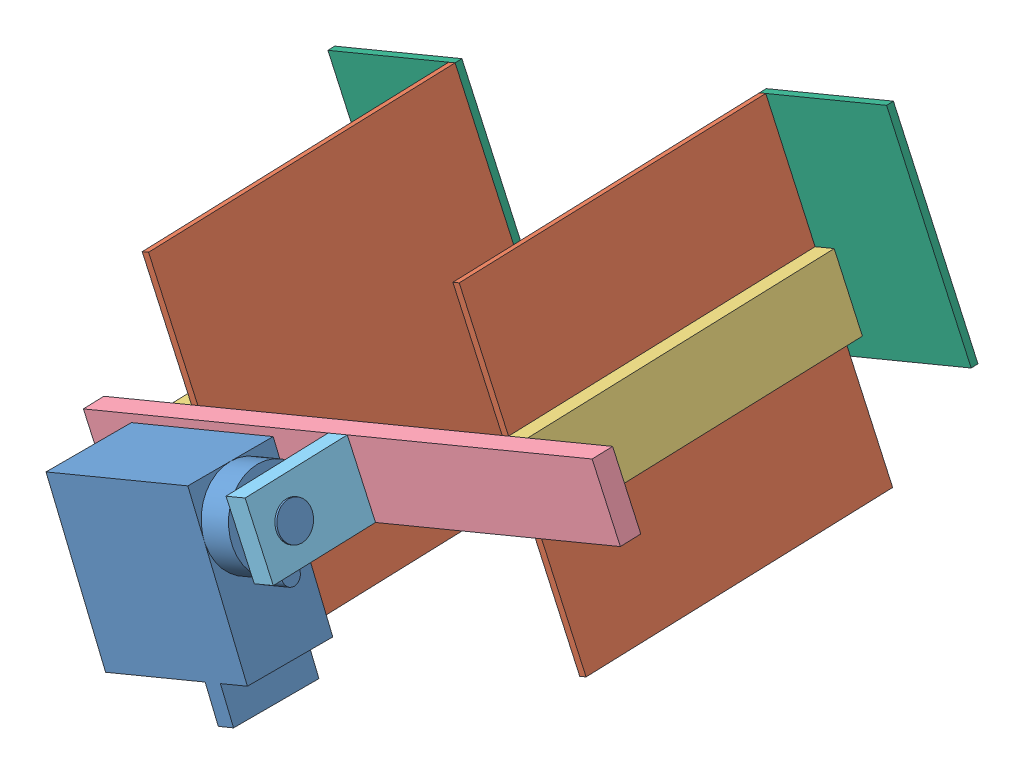
SolidWorks assembly gripper, configuration Default. Lengths in mm.
Overall size (92.65 69.09 65.38).
9 component instances, 6 part files, 25 mates.
Components (placement in the parent):
- Servo-1: Servo [Default] at (-244.1629 10.2538 215.865) x (0.383049 -0.923728 0) z (0 0 1) size (27.6 29.9 12.4)
- pad-1: pad [Default] at (-243.8055 16.9469 180.3776) x (-0.010204 0.024608 -0.999645) z (-0.923728 -0.383049 0) size (45 45 1)
- pad-2: pad [Default] at (-199.6069 35.275 180.3776) x (-0.010204 0.024608 -0.999645) z (0.923728 0.383049 0) size (45 45 1)
- arm-1: arm [Default] at (-244.7292 16.5638 180.3776) x (-0.010204 0.024608 -0.999645) z (-0.923728 -0.383049 0) size (45 10 3)
- arm-3: arm [Default] at (-198.6831 35.6581 180.3776) x (-0.010204 0.024608 -0.999645) z (0.923728 0.383049 0) size (45 10 3)
- Part12^gripper-1: Part12^gripper [Default] at (-220.2923 26.0484 202.8696) x (0.010204 -0.024608 0.999645) z (-0.923728 -0.383049 0) size (3 10 80) (virtual)
- Part13^gripper-1: Part13^gripper [Default] at (-221.5708 25.2154 213.3659) x (0.923728 0.383049 0) z (0.010204 -0.024608 0.999645) size (3 10 15) (virtual)
- Part14^gripper-1: Part14^gripper [Default] at (-256.1442 20.5956 158.0854) x (0.923728 0.383049 0) z (-0.382913 0.9234 0.02664) size (20 1 30) (virtual)
- Part14^gripper-2: Part14^gripper [Default] at (-193.4812 46.6093 157.0858) x (-0.923728 -0.383049 0) z (-0.382913 0.9234 0.02664) size (20 1 30) (virtual)
Mates (geometry in assembly coordinates):
- Coincident6: coincident aligned: plane of pad-1 through (-236.3432 -3.659 157.2862) normal (-0.010204 0.024608 -0.999645); plane of arm-1 through (-249.6445 20.5854 158.0188) normal (-0.010204 0.024608 -0.999645)
- Parallel1: parallel aligned: plane of pad-1 through (-235.884 -4.7663 202.2702) normal (0.382913 -0.9234 -0.02664); plane of arm-1 through (-245.8154 11.3514 157.7524) normal (0.382913 -0.9234 -0.02664)
- Coincident8: coincident anti-aligned: plane of pad-1 through (-244.7292 16.5638 180.3776) normal (-0.923728 -0.383049 0); plane of arm-1 through (-244.7292 16.5638 180.3776) normal (0.923728 0.383049 0)
- Coincident12: coincident: point of pad-1; point of arm-1
- Parallel3: parallel aligned: plane of pad-1 through (-236.3432 -3.659 157.2862) normal (-0.010204 0.024608 -0.999645); plane of pad-2 through (-207.5283 56.9883 158.485) normal (-0.010204 0.024608 -0.999645)
- Coincident18: coincident anti-aligned: plane of pad-2 through (-198.6831 35.6581 180.3776) normal (0.923728 0.383049 0); plane of arm-3 through (-198.6831 35.6581 180.3776) normal (-0.923728 -0.383049 0)
- Coincident19: coincident aligned: plane of pad-2 through (-207.5283 56.9883 158.485) normal (-0.010204 0.024608 -0.999645); plane of arm-3 through (-194.227 32.7439 157.7524) normal (-0.010204 0.024608 -0.999645)
- Coincident20: coincident: point of pad-2; point of arm-3
- Coincident23: coincident aligned: plane of pad-1 through (-236.3432 -3.659 157.2862) normal (-0.010204 0.024608 -0.999645); plane of pad-2 through (-207.5283 56.9883 158.485) normal (-0.010204 0.024608 -0.999645)
- Parallel5: parallel anti-aligned: plane of pad-1 through (-243.8055 16.9469 180.3776) normal (0.923728 0.383049 0); plane of pad-2 through (-199.6069 35.275 180.3776) normal (-0.923728 -0.383049 0)
- Coincident25: coincident aligned: plane of pad-1 through (-235.884 -4.7663 202.2702) normal (0.382913 -0.9234 -0.02664); plane of pad-2 through (-189.838 14.3279 202.2702) normal (0.382913 -0.9234 -0.02664)
- Coincident26: coincident aligned: plane of arm-3 through (-198.0561 41.9779 158.0188) normal (-0.382913 0.9234 0.02664); plane of Part12^gripper-1 through (-259.1254 15.2696 206.0018) normal (-0.382913 0.9234 0.02664)
- Coincident27: coincident anti-aligned: plane of arm-1 through (-249.1853 19.478 203.0028) normal (0.010204 -0.024608 0.999645); plane of Part12^gripper-1 through (-220.2923 26.0484 202.8696) normal (-0.010204 0.024608 -0.999645)
- Coincident29: coincident anti-aligned: plane of Part12^gripper-1 through (-220.2617 25.9745 205.8686) normal (0.010204 -0.024608 0.999645); plane of Part13^gripper-1 through (-220.7907 31.1661 206.0018) normal (-0.010204 0.024608 -0.999645)
- Parallel6: parallel aligned: plane of Part12^gripper-1 through (-259.1254 15.2696 206.0018) normal (-0.923728 -0.383049 0); plane of Part13^gripper-1 through (-221.5708 25.2154 213.3659) normal (-0.923728 -0.383049 0)
- Coincident31: coincident aligned: plane of Part12^gripper-1 through (-259.1254 15.2696 206.0018) normal (-0.382913 0.9234 0.02664); plane of Part13^gripper-1 through (-220.7907 31.1661 206.0018) normal (-0.382913 0.9234 0.02664)
- Coincident32: coincident: point of Part12^gripper-1; point of Part13^gripper-1
- Concentric1: concentric anti-aligned: cylinder of Servo-1 through (-218.497 26.4179 215.865) axis (-0.923728 -0.383049 0) radius 2.5; cylinder of Part13^gripper-1 through (-221.5462 25.1535 215.865) axis (0.923728 0.383049 0) radius 2.5
- Coincident33: coincident anti-aligned: plane of Servo-1 through (-219.5917 20.4429 215.865) normal (0.923728 0.383049 0); plane of Part13^gripper-1 through (-221.5708 25.2154 213.3659) normal (-0.923728 -0.383049 0)
- Coincident36: coincident aligned: plane of pad-1 through (-253.1151 36.7867 203.469) normal (-0.382913 0.9234 0.02664); plane of Part14^gripper-1 through (-271.1354 30.6407 157.4854) normal (-0.382913 0.9234 0.02664)
- Coincident38: coincident aligned: plane of pad-1 through (-243.8055 16.9469 180.3776) normal (0.923728 0.383049 0); plane of Part14^gripper-1 through (-241.1734 10.5997 156.6862) normal (0.923728 0.383049 0)
- Coincident39: coincident aligned: plane of pad-2 through (-207.0691 55.8809 203.469) normal (-0.382913 0.9234 0.02664); plane of Part14^gripper-2 through (-189.9775 64.2662 158.485) normal (-0.382913 0.9234 0.02664)
- Coincident40: coincident anti-aligned: plane of pad-2 through (-207.5283 56.9883 158.485) normal (-0.010204 0.024608 -0.999645); plane of Part14^gripper-2 through (-193.471 46.5847 158.0854) normal (0.010204 -0.024608 0.999645)
- Coincident41: coincident aligned: plane of pad-2 through (-199.6069 35.275 180.3776) normal (-0.923728 -0.383049 0); plane of Part14^gripper-2 through (-196.9646 28.9032 157.6858) normal (-0.923728 -0.383049 0)
- Coincident42: coincident anti-aligned: plane of arm-1 through (-249.6445 20.5854 158.0188) normal (-0.010204 0.024608 -0.999645); plane of Part14^gripper-1 through (-256.1442 20.5956 158.0854) normal (0.010204 -0.024608 0.999645)
